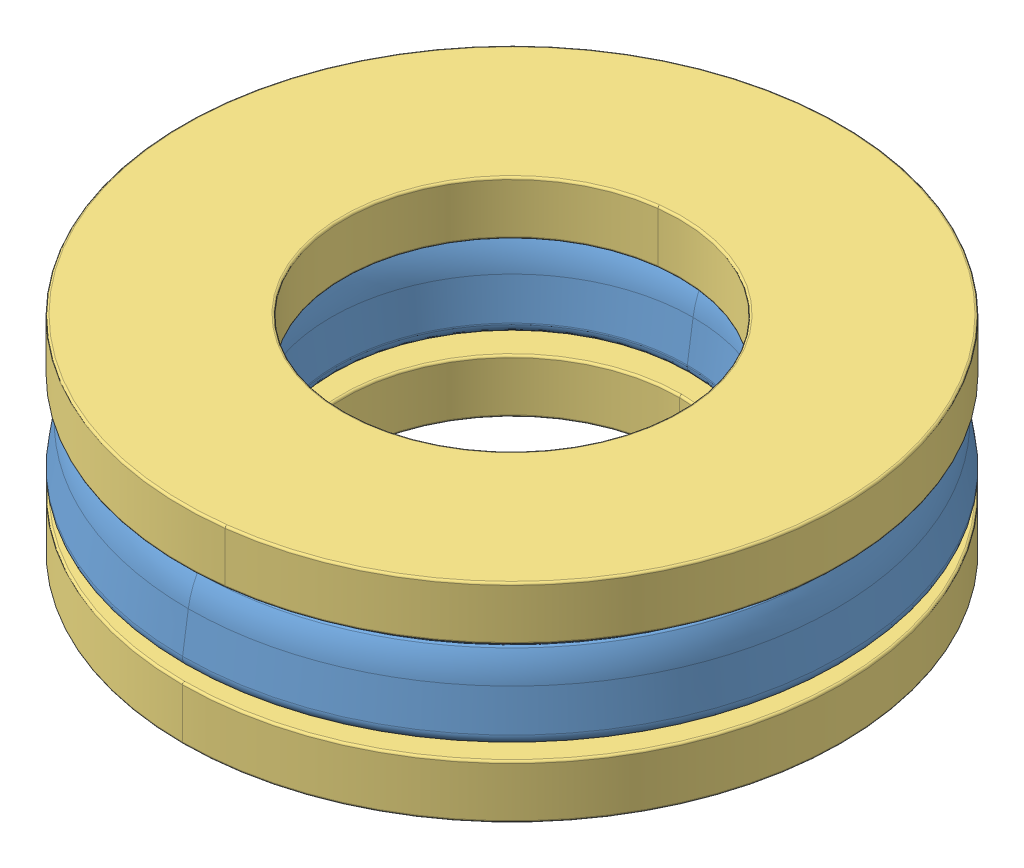
SolidWorks assembly 1613-0516-0008, configuration Default. Lengths in mm.
Overall size (17.52 4.96 17.52).
13 component instances, 3 part files, 0 mates.
Components (placement in the parent):
- 1613-0516-0008.STEP-1: 1613-0516-0008.STEP [Default] at origin size (17.52 4.96 17.52)
  - 1613-0516-0008 carriage.STEP-1: 1613-0516-0008 carriage.STEP [Default] at (-23.0253 -4.8501 14.8236) size (15.72 1.83 15.72)
  - 1613-0516-0008 ball.STEP-1: 1613-0516-0008 ball.STEP [Default] at (-28.8255 -3.9351 16.4353) size (3 3 3)
  - 1613-0516-0008 ball.STEP-2: 1613-0516-0008 ball.STEP [Default] at (-26.4325 -3.9351 19.7866) x (0.766044 0 -0.642788) z (0.642788 0 0.766044) size (3 3 3)
  - 1613-0516-0008 ball.STEP-3: 1613-0516-0008 ball.STEP [Default] at (-22.4452 -3.9351 20.8156) x (0.173648 0 -0.984808) z (0.984808 0 0.173648) size (3 3 3)
  - 1613-0516-0008 ball.STEP-4: 1613-0516-0008 ball.STEP [Default] at (-18.7293 -3.9351 19.0408) x (-0.5 0 -0.866025) z (0.866025 0 -0.5) size (3 3 3)
  - 1613-0516-0008 ball.STEP-5: 1613-0516-0008 ball.STEP [Default] at (-17.0236 -3.9351 15.2928) x (-0.939693 0 -0.34202) z (0.34202 0 -0.939693) size (3 3 3)
  - 1613-0516-0008 ball.STEP-6: 1613-0516-0008 ball.STEP [Default] at (-18.1261 -3.9351 11.3252) x (-0.939693 0 0.34202) z (-0.34202 0 -0.939693) size (3 3 3)
  - 1613-0516-0008 ball.STEP-7: 1613-0516-0008 ball.STEP [Default] at (-21.521 -3.9351 8.9945) x (-0.5 0 0.866025) z (-0.866025 0 -0.5) size (3 3 3)
  - 1613-0516-0008 ball.STEP-8: 1613-0516-0008 ball.STEP [Default] at (-25.6197 -3.9351 9.3913) x (0.173648 0 0.984808) z (-0.984808 0 0.173648) size (3 3 3)
  - 1613-0516-0008 ball.STEP-9: 1613-0516-0008 ball.STEP [Default] at (-28.5045 -3.9351 12.3299) x (0.766044 0 0.642788) z (-0.642788 0 0.766044) size (3 3 3)
  - 1613-0516-0008 washer (8mm ID x 15.72mm OD).STEP-1: 1613-0516-0008 washer (8mm ID x 15.72mm OD).STEP [Default] at (-23.0253 -6.4151 14.8236) size (15.72 1.28 15.72)
  - 1613-0516-0008 washer (8mm ID x 15.72mm OD).STEP-2: 1613-0516-0008 washer (8mm ID x 15.72mm OD).STEP [Default] at (-23.0253 -1.4551 14.8236) x (0.992523 0 -0.12206) z (-0.12206 0 -0.992523) size (15.72 1.28 15.72)
